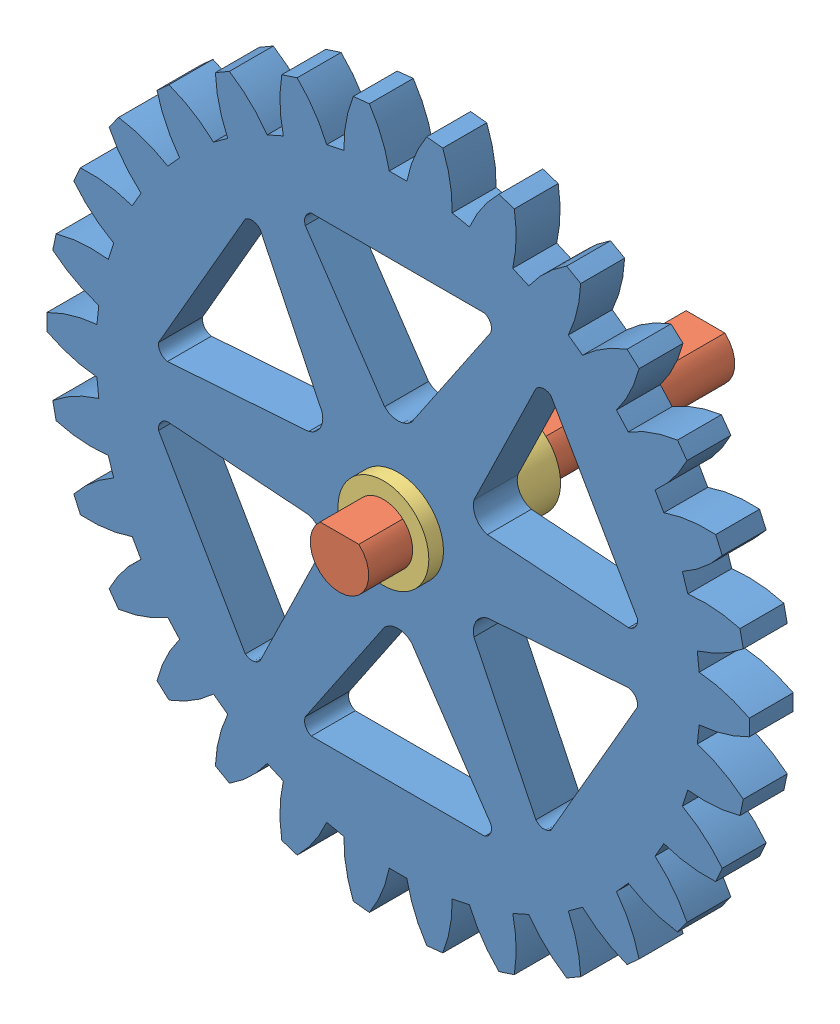
SolidWorks assembly thirdShaft, configuration Default. Lengths in mm.
Overall size (48 47.84 15).
4 component instances, 3 part files, 7 mates.
Components (placement in the parent):
- root_gear-1: root_gear [30T 1.5Mod] at (24.7057 20.8305 13.7406) size (48 47.84 3)
- axle-1: axle [15mm tall] at (24.7057 20.8305 20.7406) size (4 3.5 15)
- spacer-1: spacer [5mm tall] at (24.7057 20.8305 8.7406) size (6.2 6.2 5)
- spacer-2: spacer [1mm tall] at (24.7057 20.8305 16.7406) size (6.2 6.2 1)
Mates (geometry in assembly coordinates):
- Concentric1: concentric aligned: cylinder of root_gear-1 through (24.7057 20.8305 13.7406) axis (0 0 1) radius 2; cylinder of axle-1 through (24.7057 20.8305 5.7406) axis (0 0 1) radius 2
- Coincident1: coincident anti-aligned: plane of root_gear-1 through (23.3828 22.3305 13.7406) normal (0 -1 0); plane of axle-1 through (26.0285 22.3305 5.7406) normal (0 1 0)
- Concentric2: concentric anti-aligned: cylinder of axle-1 through (24.7057 20.8305 5.7406) axis (0 0 1) radius 2; cylinder of spacer-2 through (24.7057 20.8305 17.7406) axis (0 0 -1) radius 2
- Distance1: distance = 3 mm aligned: plane of spacer-2 through (24.7057 20.8305 17.7406) normal (0 0 1); plane of axle-1 through (24.7057 20.8305 20.7406) normal (0 0 1)
- Coincident3: coincident anti-aligned: plane of root_gear-1 through (24.7057 20.8305 16.7406) normal (0 0 1); plane of spacer-2 through (24.7057 20.8305 16.7406) normal (0 0 -1)
- Concentric3: concentric anti-aligned: cylinder of axle-1 through (24.7057 20.8305 5.7406) axis (0 0 1) radius 2; cylinder of spacer-1 through (24.7057 20.8305 13.7406) axis (0 0 -1) radius 2
- Coincident4: coincident anti-aligned: plane of root_gear-1 through (24.7057 20.8305 13.7406) normal (0 0 -1); plane of spacer-1 through (24.7057 20.8305 13.7406) normal (0 0 1)
